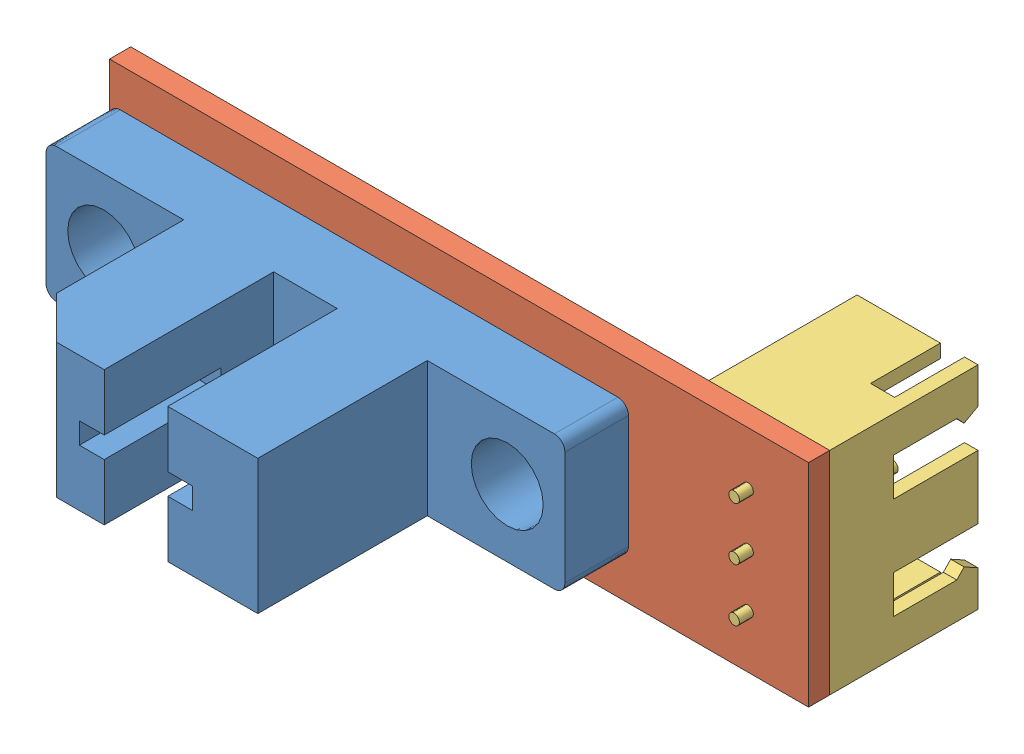
SolidWorks assembly Endstop_Opto_TCST2103, configuration Défaut. Lengths in mm.
Overall size (33 10 19).
3 component instances, 3 part files, 12 mates.
Components (placement in the parent):
- TCST2103^Endstop_Opto_TCST2103-1: TCST2103^Endstop_Opto_TCST2103 [Défaut] x (1 0 0) z (0 1 0) size (24.5 11 6.35) (virtual)
- PCB^Endstop_Opto_TCST2103-1: PCB^Endstop_Opto_TCST2103 [Défaut] x (1 0 0) z (0 0 -1) size (33 10 1) (virtual)
- Connector^Endstop_Opto_TCST2103-1: Connector^Endstop_Opto_TCST2103 [Défaut] at (0 0 -1) x (1 0 0) z (0 0 -1) size (5.71 10 8.66) (virtual)
Mates (geometry in assembly coordinates):
- Sur place1: in place: plane of TCST2103^Endstop_Opto_TCST2103-1 through (0 0 0) normal (0 1 0); moOrthogonalPlaneRef_w of TCST2103^Endstop_Opto_TCST2103-1 through (0 0 0) normal (0 0 -1); line of TCST2103^Endstop_Opto_TCST2103-1 through (55 -55 0) axis (0 0 1); unknown of TCST2103^Endstop_Opto_TCST2103-1
- Coïncidente1: coincident aligned: plane of assembly through (0 0 0) normal (0 1 0); plane of assembly through (0 0 0) normal (0 1 0)
- Coïncidente2: coincident aligned: plane of TCST2103^Endstop_Opto_TCST2103-1 through (0 0 0) normal (0 0 -1)
- Coïncidente3: coincident anti-aligned: plane of TCST2103^Endstop_Opto_TCST2103-1 through (0 0 0) normal (1 0 0)
- Sur place2: in place: plane of TCST2103^Endstop_Opto_TCST2103-1 through (-12.25 3.175 0) normal (0 0 -1); plane of ? through (0 0 0) normal (0 0 -1); plane of TCST2103^Endstop_Opto_TCST2103-1 through (-12.25 3.175 0) normal (0 0 -1); line of ? through (-55 0 0) axis (0 0 1); plane of TCST2103^Endstop_Opto_TCST2103-1 through (-12.25 3.175 0) normal (0 0 -1); plane of ? through (0 0 0) normal (-1 0 0); plane of TCST2103^Endstop_Opto_TCST2103-1 through (-12.25 3.175 0) normal (0 0 -1); unknown of PCB^Endstop_Opto_TCST2103-1
- Coïncidente4: coincident aligned: plane of TCST2103^Endstop_Opto_TCST2103-1; plane of PCB^Endstop_Opto_TCST2103-1
- Coïncidente5: coincident aligned: moOrthogonalPlaneRef_w of TCST2103^Endstop_Opto_TCST2103-1 through (0 0 0) normal (0 -1 0); plane of PCB^Endstop_Opto_TCST2103-1 through (0 0 0) normal (0 -1 0)
- Coïncidente6: coincident anti-aligned: moOrthogonalPlaneRef_w of TCST2103^Endstop_Opto_TCST2103-1 through (0 0 0) normal (-1 0 0); plane of PCB^Endstop_Opto_TCST2103-1 through (0 0 0) normal (1 0 0)
- Sur place3: in place: plane of PCB^Endstop_Opto_TCST2103-1 through (0 0 -1) normal (0 0 -1); plane of ? through (0 0 -1) normal (0 0 -1); plane of PCB^Endstop_Opto_TCST2103-1 through (0 0 -1) normal (0 0 -1); unknown of ?; plane of PCB^Endstop_Opto_TCST2103-1 through (0 0 -1) normal (0 0 -1); plane of ? through (0 0 -1) normal (-1 0 0); plane of PCB^Endstop_Opto_TCST2103-1 through (0 0 -1) normal (0 0 -1); unknown of Connector^Endstop_Opto_TCST2103-1
- Coïncidente7: coincident aligned: plane of PCB^Endstop_Opto_TCST2103-1; plane of Connector^Endstop_Opto_TCST2103-1
- Coïncidente8: coincident aligned: moOrthogonalPlaneRef_w of PCB^Endstop_Opto_TCST2103-1 through (0 0 -1) normal (0 -1 0); plane of Connector^Endstop_Opto_TCST2103-1 through (0 0 -1) normal (0 -1 0)
- Coïncidente9: coincident anti-aligned: moOrthogonalPlaneRef_w of PCB^Endstop_Opto_TCST2103-1 through (0 0 -1) normal (-1 0 0); plane of Connector^Endstop_Opto_TCST2103-1 through (0 0 -1) normal (1 0 0)
